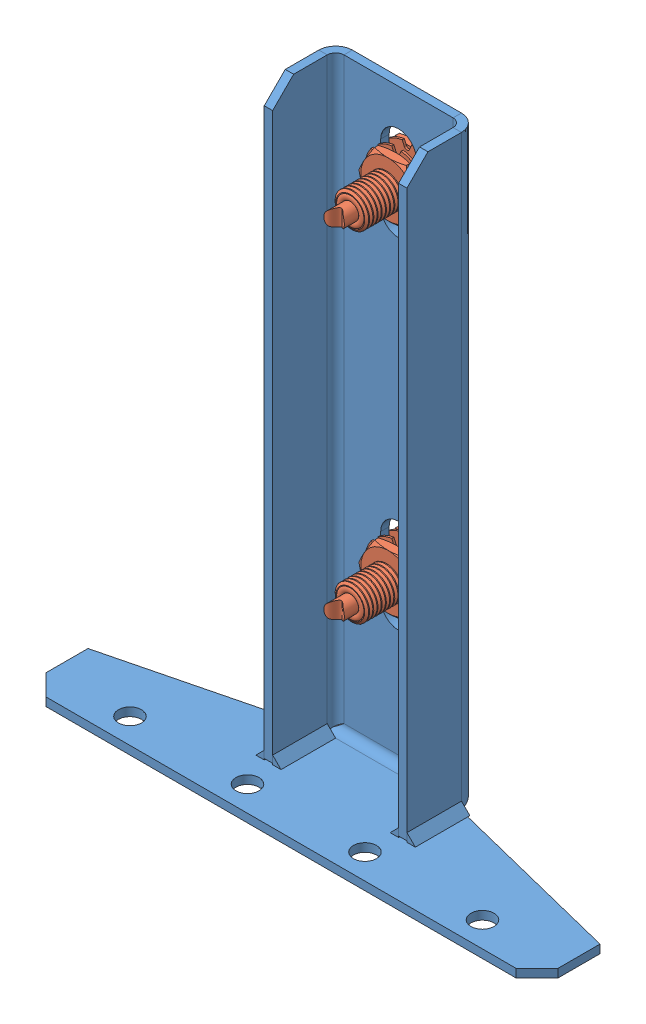
SolidWorks assembly Стойка датчиков высоты, configuration Нижний уровень. Lengths in mm.
Overall size (122 142.01 33).
3 component instances, 2 part files, 6 mates.
Components (placement in the parent):
- Держаттель датчиков высоты-1: Держаттель датчиков высоты [По умолчанию<Как обработанный >] at origin
- PS2-08M16-xxxx K-Mega-1: PS2-08M16-xxxx K-Mega [OFF] at (0 0 -4.5) x (0 0 -1) z (0 1 0)
- PS2-08M16-xxxx K-Mega-2: PS2-08M16-xxxx K-Mega [ON] at (0 -81 -4.5) x (0 0 -1) z (0 1 0) size (21.05 15.01 14.83)
Mates (geometry in assembly coordinates):
- Совпадение1: coincident anti-aligned: plane of Держаттель датчиков высоты-1 through (-15 20 0) normal (0 0 1); plane of PS2-08M16-xxxx K-Mega-1 through (0 0 0) normal (0 0 -1)
- Симметричный1: symmetric aligned: plane of Держаттель датчиков высоты-1 through (-17 20 0) normal (-1 0 0); plane of Держаттель датчиков высоты-1 through (17 20 0) normal (1 0 0); plane of PS2-08M16-xxxx K-Mega-1
- Совпадение2: coincident aligned: plane of PS2-08M16-xxxx K-Mega-1 through (0 0 -4.5) normal (0 1 0); plane of assembly through (0 0 0) normal (0 1 0)
- Симметричный2: symmetric aligned: plane of Держаттель датчиков высоты-1 through (-17 20 0) normal (-1 0 0); plane of Держаттель датчиков высоты-1 through (17 20 0) normal (1 0 0); plane of PS2-08M16-xxxx K-Mega-2
- Расстояние1: distance = 41 mm anti-aligned: plane of PS2-08M16-xxxx K-Mega-2 through (0 -81 -4.5) normal (0 1 0); plane of Держаттель датчиков высоты-1 through (-13 -122 0) normal (0 -1 0)
- Совпадение4: coincident anti-aligned: plane of Держаттель датчиков высоты-1 through (-15 20 -2) normal (0 0 -1); plane of PS2-08M16-xxxx K-Mega-2 through (0 -81 -2) normal (0 0 1)
